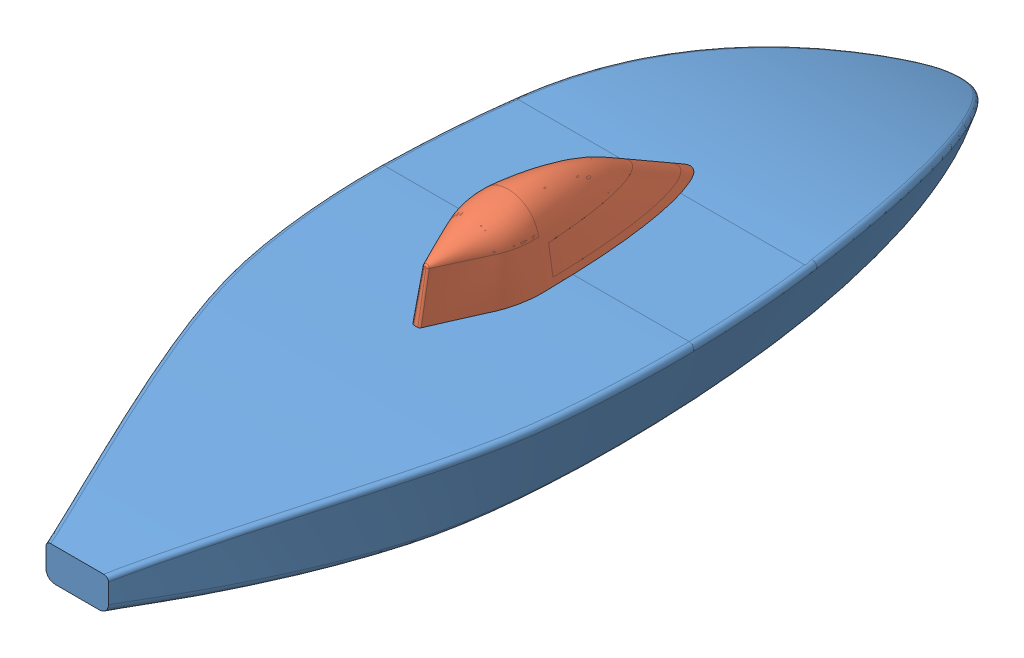
SolidWorks assembly Assem9, configuration Default. Lengths in mm.
Overall size (2219.22 1153.36 5012.29).
2 component instances, 2 part files, 0 mates.
Components (placement in the parent):
- Alain Wide Body (Double Naca Low nose)-1: Alain Wide Body (Double Naca Low nose) [Default] at (833.3868 1826.7668 4930.854) size (2219.22 992.64 5012.29)
- windshileld4-1: windshileld4 [Default] at (660.4826 1813.5254 2547.6437) x (0 0 1) z (-1 0 0) size (1688.13 400.44 575.69)
